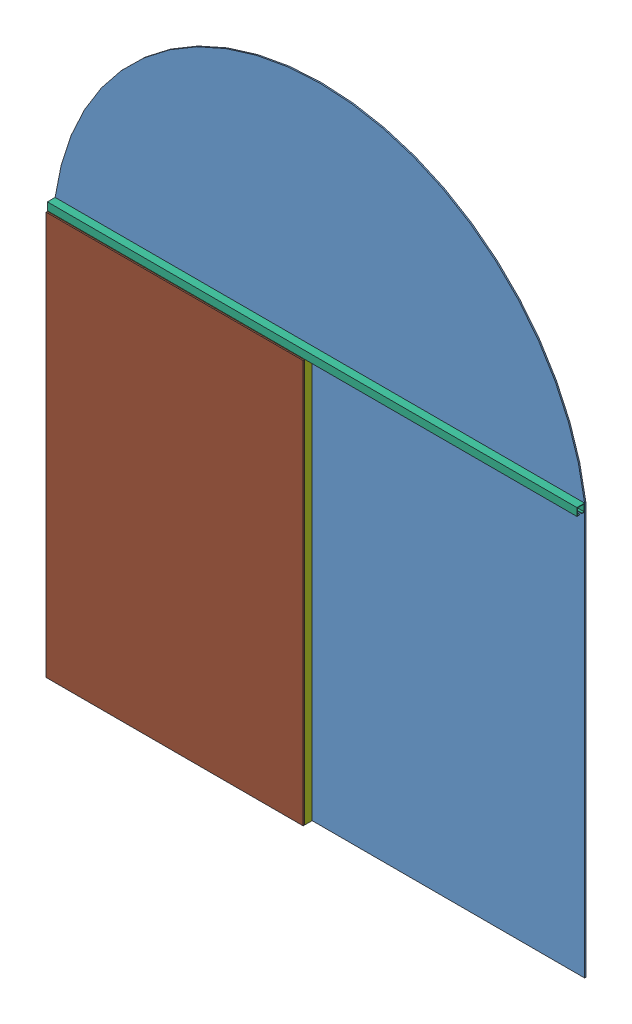
SolidWorks assembly FullFront, configuration Default. Lengths in mm.
Overall size (2060 2500 40).
35 component instances, 11 part files, 9 mates.
Components (placement in the parent):
- Front_SolarDryer-1: Front_SolarDryer [Default] at origin size (2060 2500 5)
- FullDoorWithBar-1: FullDoorWithBar [Default] at (0 785 17.5) x (0 0 1) z (-1 0 0) size (30 1600 2060)
  - FullCar-1: FullCar [Default] at (0 -6.25 870) size (25 18.99 35)
    - Carriage-1: Carriage [Default] at origin size (24.16 8.5 35)
    - LockWheels-1: LockWheels [Default] at (12.5 0 7.5) x (0 0.86398 0.503526) z (0 -0.503526 0.86398) size (3.5 7.63 3.5)
    - LockWheels-2: LockWheels [Default] at (12.5 0 -7.5) x (0 -0.86398 0.503526) z (0 -0.503526 -0.86398) size (3.5 7.63 3.5)
    - LockWheels-3: LockWheels [Default] at (-12.5 0 7.5) x (0 -0.86398 -0.503526) z (0 -0.503526 0.86398) size (3.5 7.63 3.5)
    - LockWheels-4: LockWheels [Default] at (-12.5 0 -7.5) x (0 0.86398 -0.503526) z (0 -0.503526 -0.86398) size (3.5 7.63 3.5)
    - WheelCarriage-1: WheelCarriage [Default] at (9.25 0 7.5) x (0 -0.862763 -0.505608) z (1 0 0) size (13.5 13.5 3.5)
    - WheelCarriage-2: WheelCarriage [Default] at (9.25 0 -7.5) x (0 -0.862763 0.505608) z (-1 0 0) size (13.5 13.5 3.5)
    - WheelCarriage-3: WheelCarriage [Default] at (-9.25 0 7.5) x (0 -0.862763 -0.505608) z (1 0 0) size (13.5 13.5 3.5)
    - WheelCarriage-4: WheelCarriage [Default] at (-9.25 0 -7.5) x (0 -0.862763 0.505608) z (-1 0 0) size (13.5 13.5 3.5)
    - Support-1: Support [Default] at (0 -7.5 0) x (0 0 1) z (-1 0 0) size (13 7.5 7)
  - FrontHorizontalBar-1: FrontHorizontalBar [Default] at origin size (30 30 2060)
  - Door-1: Door [Default] at (0 -801.125 530) x (0 0 1) z (-1 0 0) size (1000 1572.75 30)
  - Lid_Locker-1: Lid_Locker [Default] at (-3.725 -13.75 870) x (0 0 1) z (-1 0 0) size (13.9 5.5 1.7)
  - FullCar-4: FullCar [Default] at (0 -6.25 190) size (25 18.99 35)
    - Carriage-1: Carriage [Default] at origin size (24.16 8.5 35)
    - LockWheels-1: LockWheels [Default] at (12.5 0 7.5) x (0 0.86398 0.503526) z (0 -0.503526 0.86398) size (3.5 7.63 3.5)
    - LockWheels-2: LockWheels [Default] at (12.5 0 -7.5) x (0 -0.86398 0.503526) z (0 -0.503526 -0.86398) size (3.5 7.63 3.5)
    - LockWheels-3: LockWheels [Default] at (-12.5 0 7.5) x (0 -0.86398 -0.503526) z (0 -0.503526 0.86398) size (3.5 7.63 3.5)
    - LockWheels-4: LockWheels [Default] at (-12.5 0 -7.5) x (0 0.86398 -0.503526) z (0 -0.503526 -0.86398) size (3.5 7.63 3.5)
    - WheelCarriage-1: WheelCarriage [Default] at (9.25 0 7.5) x (0 -0.862763 -0.505608) z (1 0 0) size (13.5 13.5 3.5)
    - WheelCarriage-2: WheelCarriage [Default] at (9.25 0 -7.5) x (0 -0.862763 0.505608) z (-1 0 0) size (13.5 13.5 3.5)
    - WheelCarriage-3: WheelCarriage [Default] at (-9.25 0 7.5) x (0 -0.862763 -0.505608) z (1 0 0) size (13.5 13.5 3.5)
    - WheelCarriage-4: WheelCarriage [Default] at (-9.25 0 -7.5) x (0 -0.862763 0.505608) z (-1 0 0) size (13.5 13.5 3.5)
    - Support-1: Support [Default] at (0 -7.5 0) x (0 0 1) z (-1 0 0) size (13 7.5 7)
  - Lid_Locker-2: Lid_Locker [Default] at (-3.725 -13.75 190) x (0 0 1) z (-1 0 0) size (13.9 5.5 1.7)
  - Full_Restrictor-1: Full_Restrictor [Default] at (0 -12.75 897.6) x (-1 0 0) z (0 0 -1) size (25 10.16 20.1)
    - Lid_Restrictor-1: Lid_Restrictor [Default] at (0 8.5 10.1) x (1 0 0) z (0 0 -1) size (2.81 2.81 3)
    - Restrictor-1: Restrictor [Default] at origin size (25 9.5 19.9)
  - Full_Restrictor-2: Full_Restrictor [Default] at (0 -12.75 -897.6) size (25 10.16 20.1)
    - Lid_Restrictor-1: Lid_Restrictor [Default] at (0 8.5 10.1) x (1 0 0) z (0 0 -1) size (2.81 2.81 3)
    - Restrictor-1: Restrictor [Default] at origin size (25 9.5 19.9)
- DoorCover-1: DoorCover [Default] at (-530 -16.125 35) size (1000 1567.75 5)
Mates (geometry in assembly coordinates):
- Coincident2: coincident aligned: plane of Front_SolarDryer-1 through (0 0 0) normal (0 0 1)
- Coincident3: coincident aligned: plane of Front_SolarDryer-1 through (0 0 0) normal (0 1 0)
- Coincident4: coincident aligned: plane of Front_SolarDryer-1 through (0 0 0) normal (1 0 0)
- Coincident5: coincident anti-aligned: plane of Front_SolarDryer-1 through (0 660.6111 2.5) normal (0 0 1); plane of FullDoorWithBar-1/FrontHorizontalBar-1 through (-1030 770 2.5) normal (0 0 -1)
- Coincident6: coincident aligned: line of Front_SolarDryer-1 through (-1030 770 2.5) axis (1 0 0); line of FullDoorWithBar-1/FrontHorizontalBar-1 through (-1030 770 2.5) axis (1 0 0)
- Coincident7: coincident aligned: plane of Front_SolarDryer-1 through (-1030 800 2.5) normal (-1 0 0); plane of FullDoorWithBar-1/FrontHorizontalBar-1 through (-1030 785 17.5) normal (-1 0 0)
- Coincident8: coincident anti-aligned: plane of FullDoorWithBar-1/Door-1 through (-530 -16.125 32.5) normal (0 0 1); plane of DoorCover-1 through (-530 -16.125 32.5) normal (0 0 -1)
- Coincident9: coincident aligned: plane of FullDoorWithBar-1/Door-1 through (-1030 767.75 2.5) normal (-1 0 0); plane of DoorCover-1 through (-1030 767.75 37.5) normal (-1 0 0)
- Coincident10: coincident aligned: plane of FullDoorWithBar-1/Door-1 through (-30 767.75 2.5) normal (0 1 0); plane of DoorCover-1 through (-30 767.75 37.5) normal (0 1 0)
